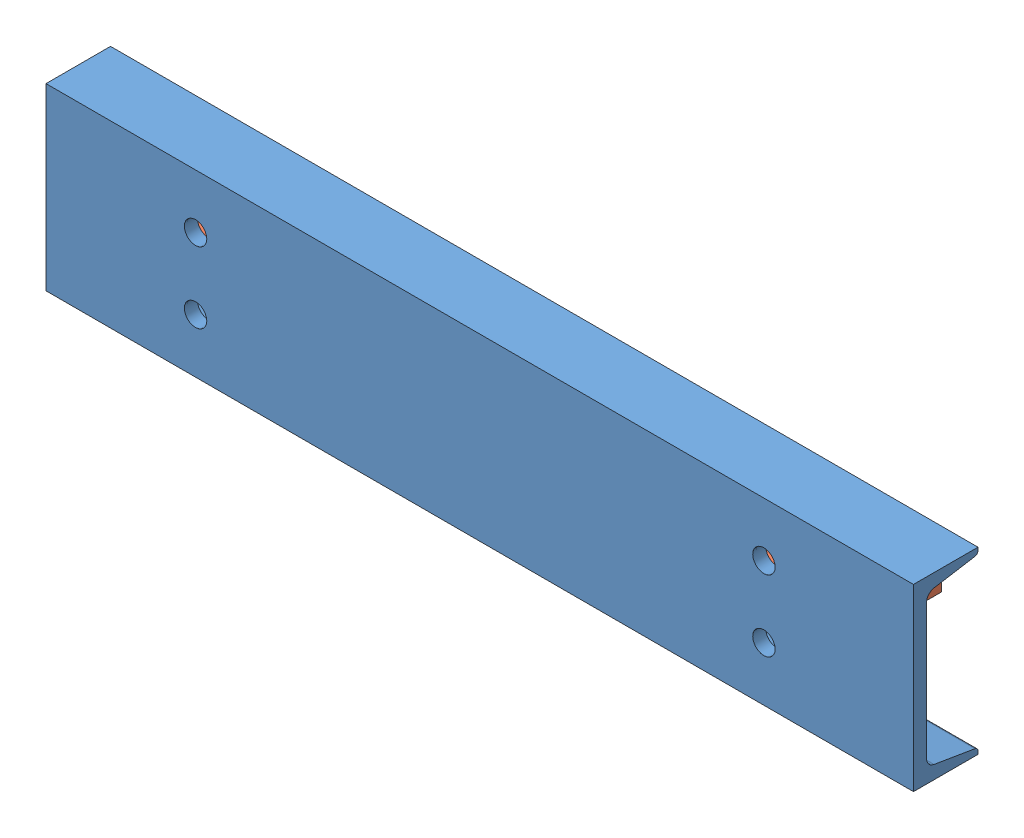
SolidWorks assembly 01-013-00-0, configuration Default. Lengths in mm.
Overall size (736.6 152.4 87.3).
2 component instances, 2 part files, 4 mates.
Components (placement in the parent):
- 01-011-00-0-1: 01-011-00-0 [Default] at origin size (736.6 152.4 54.79)
- 01-012-00-0-1: 01-012-00-0 [Default] at (-304.8 -4.7625 16.2941) size (609.6 9.53 76.2)
Mates (geometry in assembly coordinates):
- Coincident1: coincident anti-aligned: plane of 01-011-00-0-1 through (368.3 57.3918 16.2941) normal (0 0 -1); plane of 01-012-00-0-1 through (-304.8 4.7625 16.2941) normal (0 0 1)
- Parallel2: parallel aligned: plane of 01-011-00-0-1 through (368.3 76.2 27.3939) normal (0 1 0); plane of 01-012-00-0-1 through (-304.8 4.7625 -59.9059) normal (0 1 0)
- Distance2: distance = 76.2 mm: plane of 01-011-00-0-1 through (368.3 76.2 27.3939) normal (0 1 0); moEndPointRef_w of 01-012-00-0-1
- Distance3: distance = 368.3 mm: moEndPointRef_w of 01-012-00-0-1; plane of 01-011-00-0-1 through (368.3 -73.7107 -24.3459) normal (1 0 0)
